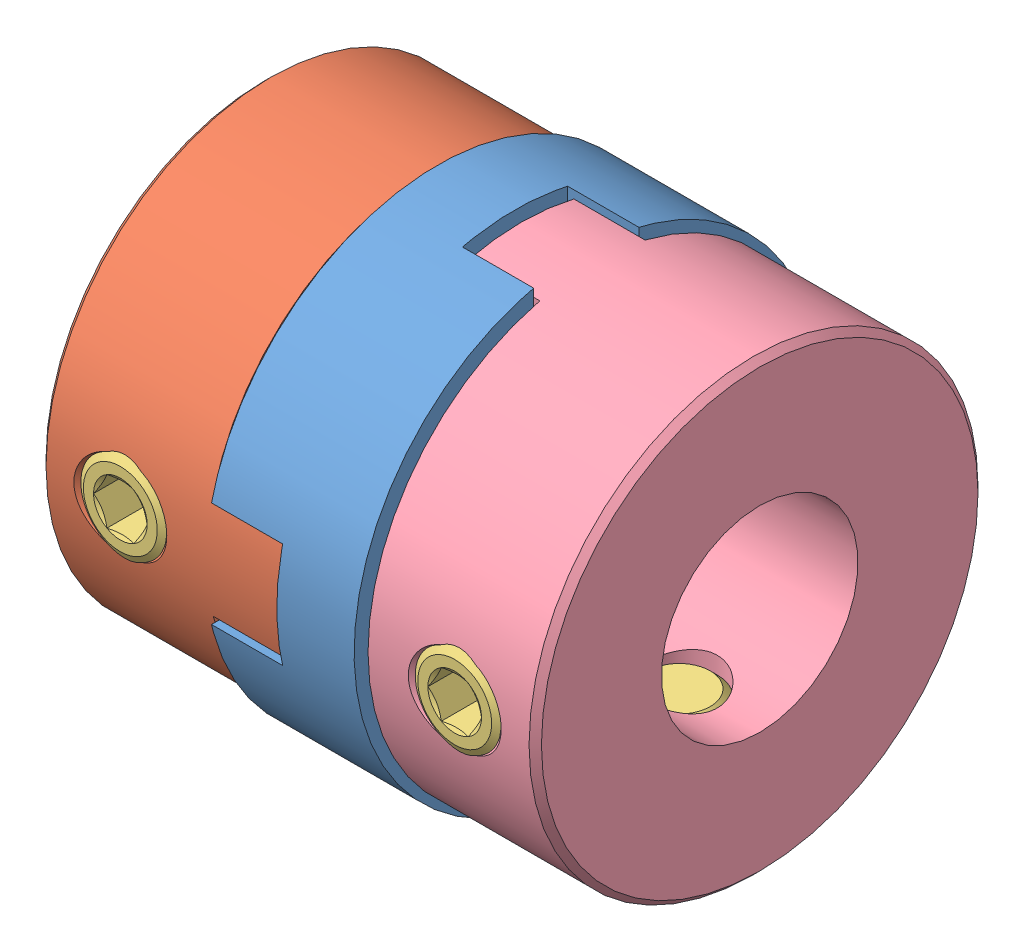
SolidWorks assembly Assem2, configuration Default. Lengths in mm.
Overall size (16 15 15).
7 component instances, 4 part files, 0 mates.
Components (placement in the parent):
- MCO_spacer15-1: MCO_spacer15 [Default] at (2.4 0 0) x (-1 0 0) z (0 -1 0) size (4.8 15 15)
- MCO15_6-1: MCO15_6 [Default] at (-8 0 0) size (7.7 14.5 14.5)
- Hexagon_socket_set_screw_with_flat_point_DIN_913___M3x4-1: Hexagon_socket_set_screw_with_flat_point_DIN_913___M3x4 [Default] at (-5.4 0 7.25) x (0 0 -1) z (-1 0 0) size (4 3 3)
- Hexagon_socket_set_screw_with_flat_point_DIN_913___M3x4-2: Hexagon_socket_set_screw_with_flat_point_DIN_913___M3x4 [Default] at (-5.4 -7.25 0) x (0 1 0) z (-1 0 0) size (4 3 3)
- MCO15_6_35-1: MCO15_6_35 [Default] at (8 0 0) x (-1 0 0) z (0 -1 0) size (7.7 14.5 14.5)
- Hexagon_socket_set_screw_with_flat_point_DIN_913___M3x4-3: Hexagon_socket_set_screw_with_flat_point_DIN_913___M3x4 [Default] at (5.4 -7.25 0) x (0 1 0) z (1 0 0) size (4 3 3)
- Hexagon_socket_set_screw_with_flat_point_DIN_913___M3x4-4: Hexagon_socket_set_screw_with_flat_point_DIN_913___M3x4 [Default] at (5.4 0 7.25) x (0 0 -1) z (1 0 0) size (4 3 3)
